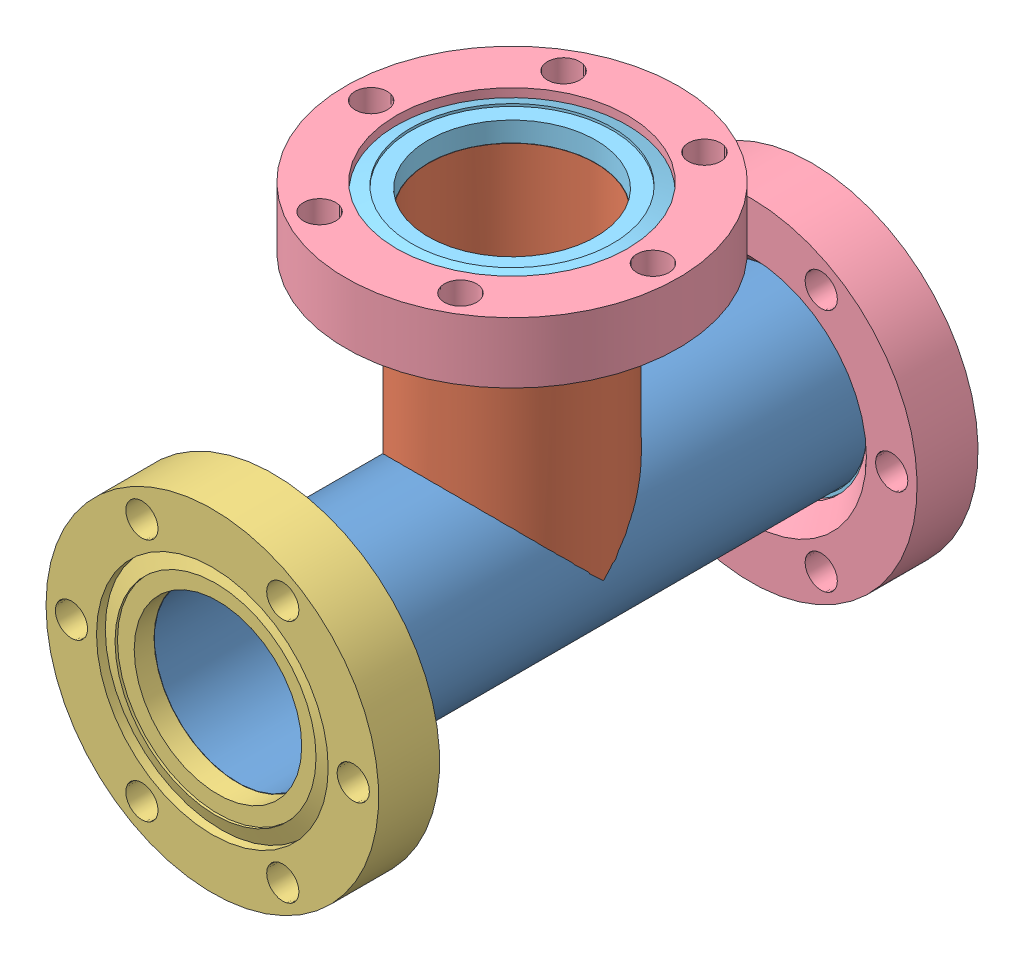
SolidWorks assembly 404002, configuration Default. Lengths in mm.
Overall size (69.34 97.13 124.92).
9 component instances, 5 part files, 0 mates.
Components (placement in the parent):
- 404002-001-1: 404002-001 [Default] at origin size (38.1 38.1 114.3)
- 404002-002-1: 404002-002 [Default] at (0 0 57.15) x (-1 0 0) z (0 1 0) size (38.1 38.1 58.53)
- 110014 (2.75 X 1.5 NR)_1-1: 110014 (2.75 X 1.5 NR)_1 [Default] at (0 0 113.2586) x (0 0 1) z (-1 0 0) size (12.7 69.34 69.34)
- 100014 (2.75 X 1.5 R)-1: 100014 (2.75 X 1.5 R) [Default] at (0 62.4586 57.15) x (0 -1 0) z (1 0 0) size (12.7 69.34 69.34)
  - 100014 (2.75 X 1.5 REC)_1-1: 100014 (2.75 X 1.5 REC)_1 [Default] at origin size (12.7 69.34 69.34)
  - 100014 (2.75 X 1.5 INS)-1: 100014 (2.75 X 1.5 INS) [Default] at (1.17 0 0) x (1 0 0) z (0 0.994423 -0.105464) size (6.96 48.1 48.1)
- 100014 (2.75 X 1.5 R)-2: 100014 (2.75 X 1.5 R) [Default] at (0 0 -5.3086) x (0 0 1) z (-1 0 0) size (12.7 69.34 69.34)
  - 100014 (2.75 X 1.5 REC)_1-1: 100014 (2.75 X 1.5 REC)_1 [Default] at origin size (12.7 69.34 69.34)
  - 100014 (2.75 X 1.5 INS)-1: 100014 (2.75 X 1.5 INS) [Default] at (1.17 0 0) x (1 0 0) z (0 0.994423 -0.105464) size (6.96 48.1 48.1)
